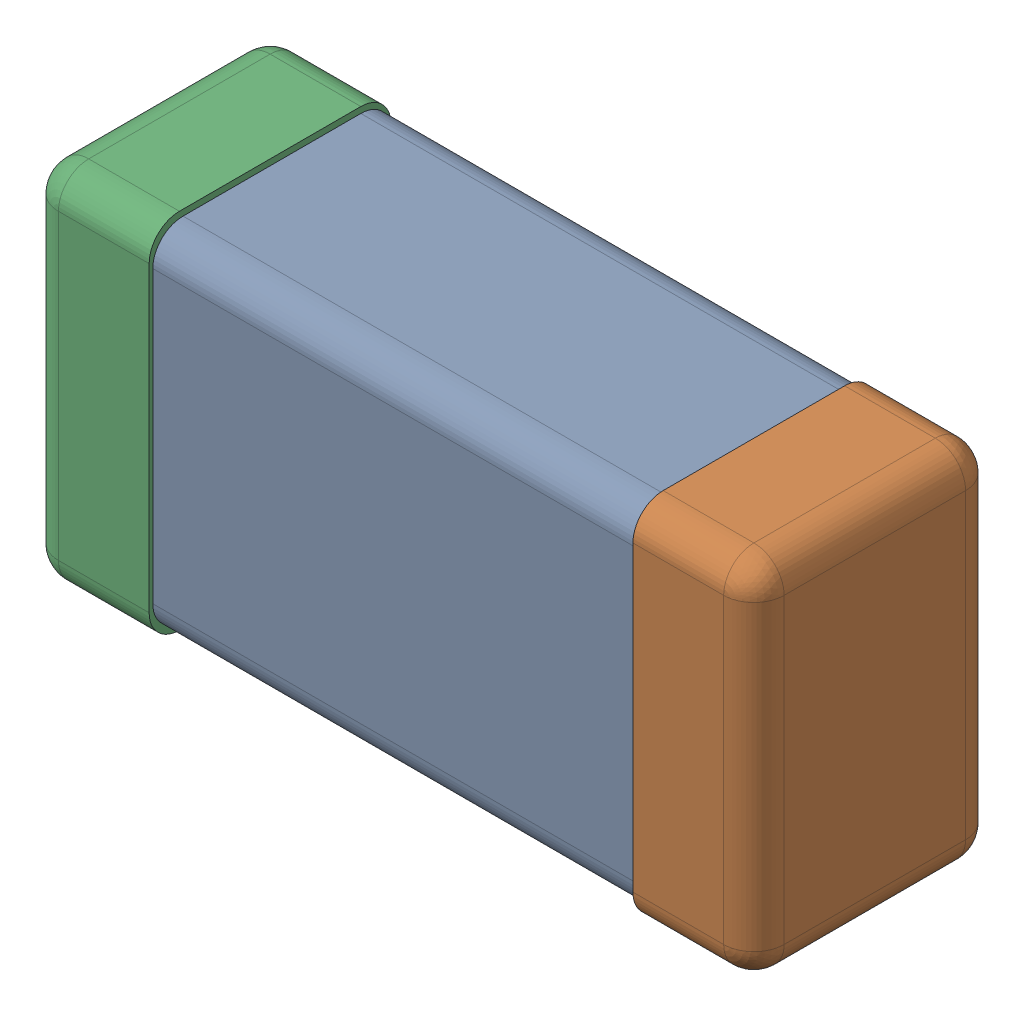
SolidWorks assembly C0201_020_15, configuration Standard. Lengths in mm.
Overall size (0.6 0.3 0.2).
3 component instances, 3 part files, 0 mates.
Components (placement in the parent):
- Part 3_2-1: Part 3_2 [Standard] at (0 0 -7.3015) size (0.5 0.29 0.2)
- Part 2_2-1: Part 2_2 [Standard] at (0 0 -7.3) size (0.1 0.3 0.2)
- Part 1_2-1: Part 1_2 [Standard] at (0 0 -7.3) size (0.1 0.3 0.2)
